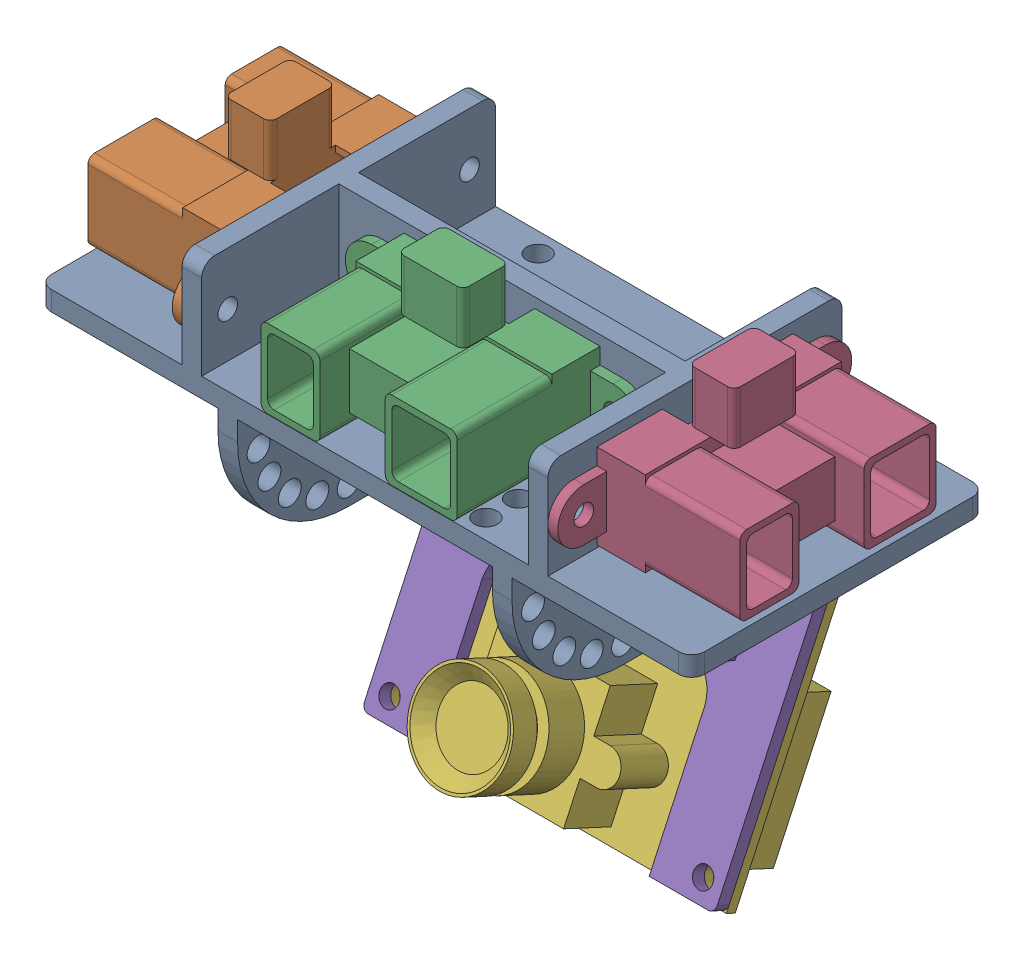
SolidWorks assembly Assem1, configuration Default. Lengths in mm.
Overall size (100 86.02 61.19).
6 component instances, 4 part files, 10 mates.
Components (placement in the parent):
- sharp holder-1: sharp holder [Default] at (-0.3832 -1.2139 0.6036) size (100 38 45)
- sharp-1: sharp [Default] at (-28.3832 8.6712 0.6036) x (0 0 -1) z (0 1 0) size (45 21.9 21)
- sharp-2: sharp [Default] at (-0.3832 8.7496 2.1036) x (-1 0 0) z (0 1 0) size (45 21.9 21)
- sharp-3: sharp [Default] at (27.6168 8.6712 0.6036) x (0 0 1) z (0 1 0) size (45 21.9 21)
- pixy holder-1: pixy holder [Default] at (-0.8075 -35.092 -16.1459) x (-1 0 0) z (0 0.907237 -0.42062) size (54 17 51.48)
- Pixy-1: Pixy [Default] at (-0.7318 -38.4261 -16.2535) x (-1 0 0) z (0 0.907237 -0.42062) size (54 31.5 50.4)
Mates (geometry in assembly coordinates):
- Coincident1: coincident aligned: circle of sharp holder-1; circle of sharp-1
- Coincident3: coincident aligned: circle of sharp holder-1; circle of sharp-1
- Coincident5: coincident aligned: circle of sharp holder-1; circle of sharp-2
- Coincident6: coincident aligned: circle of sharp holder-1; circle of sharp-2
- Coincident7: coincident aligned: circle of sharp holder-1; circle of sharp-3
- Coincident8: coincident aligned: circle of sharp holder-1; circle of sharp-3
- Coincident9: coincident aligned: circle of pixy holder-1; circle of Pixy-1
- Coincident10: coincident aligned: circle of pixy holder-1; circle of Pixy-1
- Coincident11: coincident anti-aligned: plane of sharp holder-1 through (-19.8832 -21.2139 23.1036) normal (1 0 0); plane of pixy holder-1 through (-19.8832 -4.0777 -11.7868) normal (-1 0 0)
- Concentric2: concentric aligned: cylinder of sharp holder-1 through (-50.3832 -11.2139 -17.0207) axis (1 0 0) radius 1.75; cylinder of pixy holder-1 through (-27.7318 -11.2139 -17.0207) axis (1 0 0) radius 1.75
